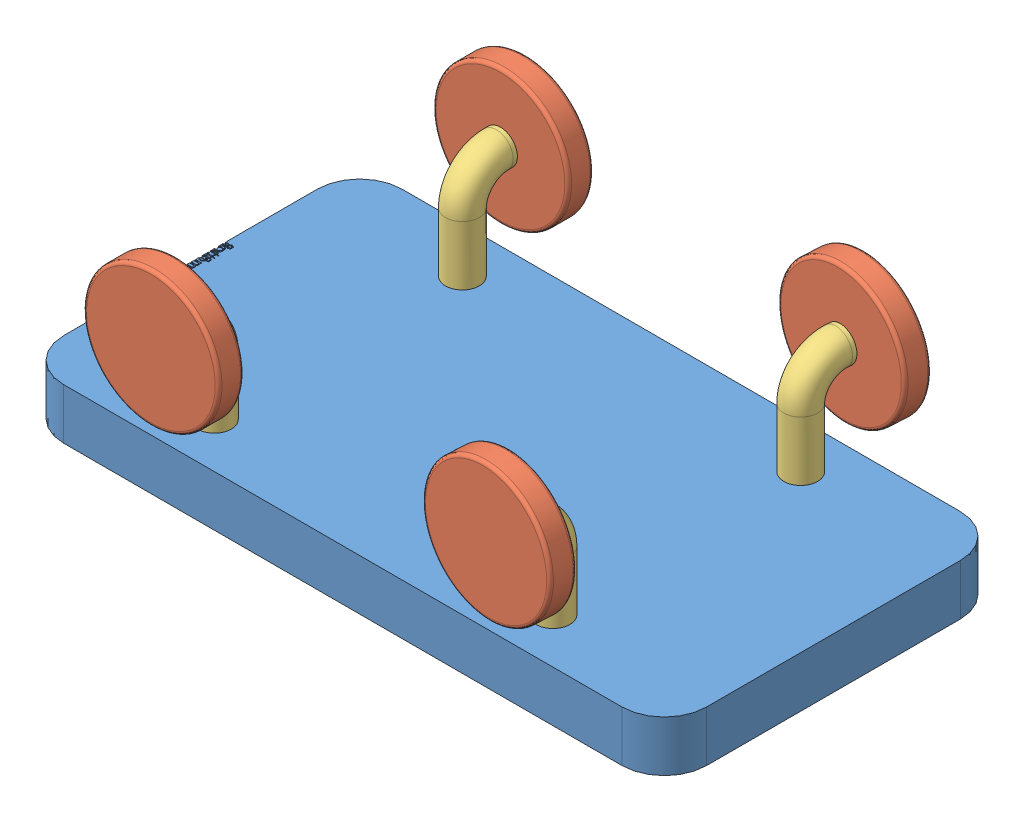
SolidWorks assembly toy_car_rev2, configuration Default. Lengths in mm.
Overall size (965.2 355.98 637.36).
9 component instances, 3 part files, 10 mates.
Components (placement in the parent):
- Chassis_rev1-1: Chassis_rev1 [Default] at origin size (965.2 76.2 508)
- Wheel_rev1-1: Wheel_rev1 [Default] at (-260.576 215.9 262.3285) x (0.396692 -0.917952 0) z (0 0 -1) size (203.2 203.2 38.1)
- connector-1: connector [Default] at (-260.576 215.9 268.6785) x (0 0 1) z (1 0 0) size (107.95 190.5 50.8)
- connector-2: connector [Default] at (242.7987 215.9 268.3422) x (-0.056029 0 0.998429) z (0.998429 0 0.056029) size (107.95 190.5 50.8)
- Wheel_rev1-2: Wheel_rev1 [Default] at (243.1545 215.9 262.0021) x (0.396069 -0.917952 0.022226) z (0.056029 0 -0.998429) size (203.2 203.2 38.1)
- connector-3: connector [Default] at (252.6254 215.9 -268.3078) x (0.06301 0 -0.998013) z (-0.998013 0 -0.06301) size (107.95 190.5 50.8)
- Wheel_rev1-3: Wheel_rev1 [Default] at (252.2253 215.9 -261.9704) x (-0.055528 0.998451 -0.003506) z (-0.06301 0 0.998013) size (203.2 203.2 38.1)
- connector-4: connector [Default] at (-260.576 215.9 -268.6785) x (0 0 -1) z (-1 0 0) size (107.95 190.5 50.8)
- Wheel_rev1-4: Wheel_rev1 [Default] at (-260.576 215.9 -262.3285) x (0.846782 0.53194 0) z (0 0 1) size (203.2 203.2 38.1)
Mates (geometry in assembly coordinates):
- ProfileCenter1: profile center aligned: circle of connector-1; circle of Chassis_rev1-1
- ProfileCenter2: profile center anti-aligned: circle of connector-1; circle of Wheel_rev1-1
- ProfileCenter3: profile center anti-aligned: circle of connector-2; circle of Wheel_rev1-2
- ProfileCenter4: profile center anti-aligned: circle of connector-3; circle of Wheel_rev1-3
- ProfileCenter5: profile center anti-aligned: circle of connector-4; circle of Wheel_rev1-4
- ProfileCenter6: profile center anti-aligned: plane of connector-4 through (-260.576 50.8 -186.1285) normal (0 -1 0); circle of Chassis_rev1-1
- ProfileCenter7: profile center aligned: plane of connector-2 through (247.4239 50.8 185.9218) normal (0 -1 0); plane of Chassis_rev1-1 through (247.4239 50.8 185.9218) normal (0 1 0)
- ProfileCenter8: profile center anti-aligned: plane of Chassis_rev1-1 through (247.4239 50.8 -185.9218) normal (0 1 0); circle of connector-3
- Parallel1: parallel anti-aligned: plane of Wheel_rev1-1 through (-260.576 215.9 243.2785) normal (0 0 -1); plane of Wheel_rev1-4 through (-260.576 215.9 -243.2785) normal (0 0 1)
- Parallel2: parallel anti-aligned: plane of Chassis_rev1-1 through (-482.6 76.2 254) normal (0 0 1); plane of Wheel_rev1-1 through (-260.576 215.9 243.2785) normal (0 0 -1)
